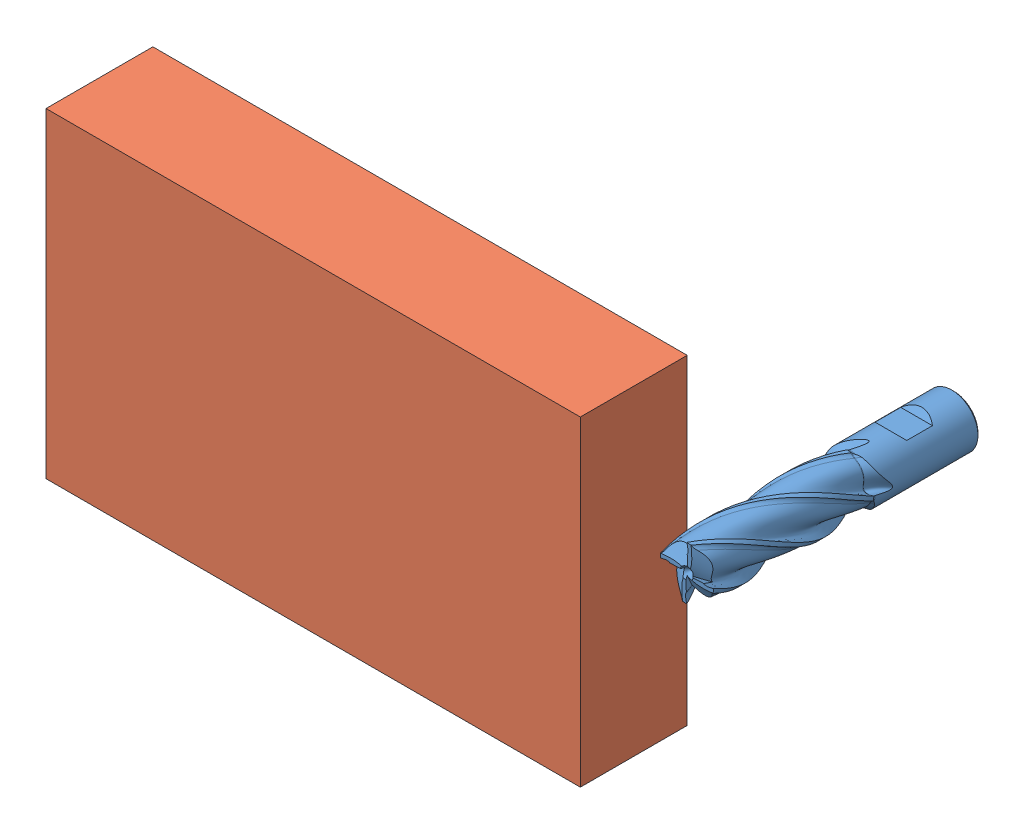
SolidWorks assembly milling_assemblyV2, configuration 默认. Lengths in mm.
Overall size (278.93 150 162.5).
2 component instances, 2 part files, 4 mates.
Components (placement in the parent):
- endmill-1: endmill [Default] at (-7.2613 -0.9019 62.6172) size (33.25 33.25 125.23)
- workpiece-1: workpiece [默认] at (-144.5613 0 225.1172) x (1 0 0) z (0 1 0) size (250 50 150)
Mates (geometry in assembly coordinates):
- 平行1: parallel aligned: plane of endmill-1 through (-7.2613 -0.9019 62.6172) normal (0 0 -1); plane of workpiece-1 through (-144.5613 0 175.1172) normal (0 0 -1)
- 重合2: coincident aligned: plane of workpiece-1 through (-144.5613 0 225.1172) normal (0 1 0); plane of assembly through (0 0 0) normal (0 1 0)
- 距离1: distance = 10 mm anti-aligned: plane of endmill-1 through (-7.2613 -0.9019 185.1172) normal (0 0 1); plane of workpiece-1 through (-144.5613 0 175.1172) normal (0 0 -1)
- 距离2: distance = 0.05 mm anti-aligned: cylinder of endmill-1 through (-7.2613 -0.9019 112.6172) axis (0 0 -1) radius 12.25; plane of workpiece-1 through (-19.5613 75 175.1172) normal (1 0 0)
